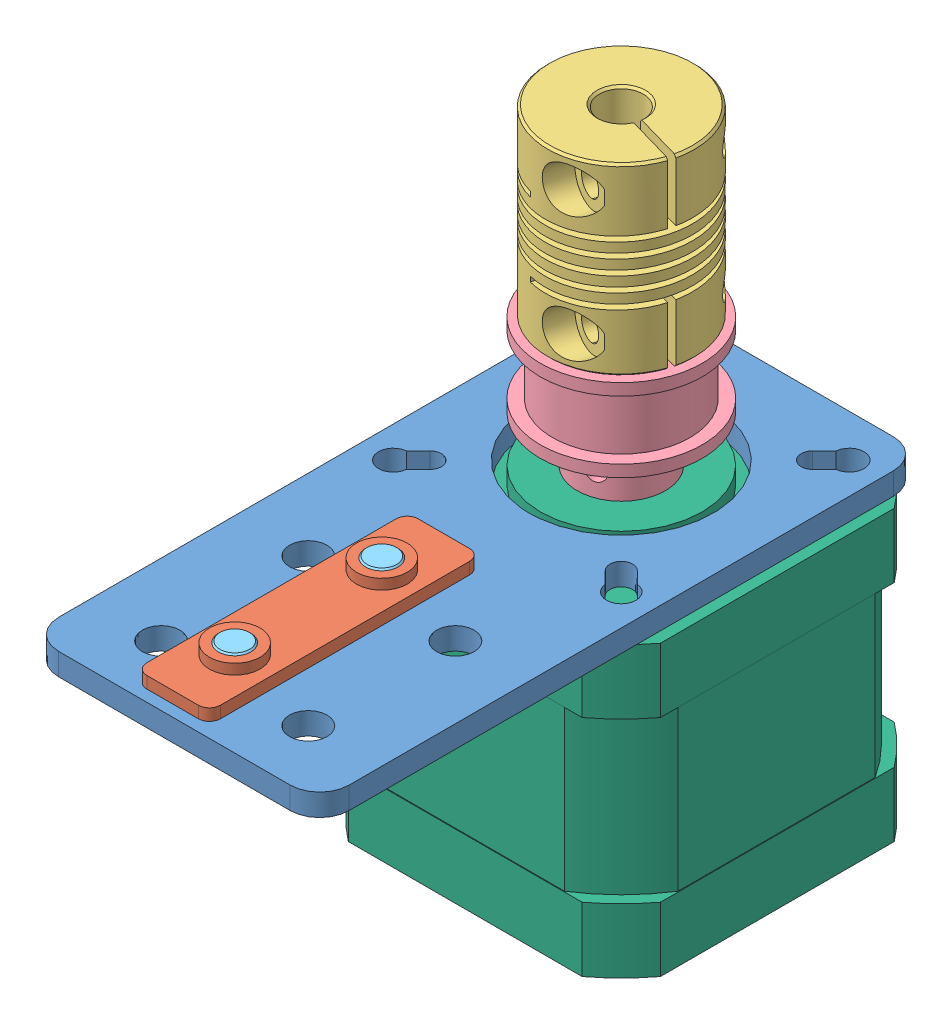
SolidWorks assembly MOTOR_MOUNT, configuration Default. Lengths in mm.
Overall size (42.42 84.14 82.24).
7 component instances, 6 part files, 14 mates.
Components (placement in the parent):
- MOD_NEMA_17_MOUNT_PLATE-1: MOD_NEMA_17_MOUNT_PLATE [Default] at (36.577 37.551 42.5841) size (39.5 3 82)
- Double Tee Nut-1: Double Tee Nut [Default] at (41.577 42.351 103.5741) x (0 0 -1) z (0 1 0) size (36.88 10 3)
- Flexible Coupling 5mm x 6mm-1: Flexible Coupling 5mm x 6mm [Default] at (36.577 57.451 42.5841) x (0.961283 0 0.275565) z (0 -1 0) size (21.03 20 25)
- GT2 Timing Pulley 30 Tooth-1: GT2 Timing Pulley 30 Tooth [Default] at (36.577 39.951 42.5841) x (0 1 0) z (0.35449 0 0.93506) size (17.5 22 22)
- LP_SH_SCREW_M5_8mm-1: LP_SH_SCREW_M5_8mm [M5 x 8] at (36.577 45.551 95.1341) x (0 1 0) z (0 0 1) size (9.62 9 9)
- LP_SH_SCREW_M5_8mm-2: LP_SH_SCREW_M5_8mm [M5 x 8] at (36.577 45.551 75.1341) x (0 1 0) z (0 0 1) size (9.62 9 9)
- NEMA_17_MOTOR-1: NEMA_17_MOTOR [Default] at (36.577 37.551 42.5841) x (1 0 0) z (0 1 0) size (42.42 42.42 60.45)
Mates (geometry in assembly coordinates):
- Concentric1: concentric anti-aligned: cylinder of MOD_NEMA_17_MOUNT_PLATE-1 through (36.577 40.551 75.1341) axis (0 -1 0) radius 2.55; cylinder of Double Tee Nut-1 through (36.577 45.351 75.1341) axis (0 1 0) radius 2.1
- Concentric2: concentric anti-aligned: cylinder of MOD_NEMA_17_MOUNT_PLATE-1 through (36.577 40.551 95.1341) axis (0 -1 0) radius 2.55; cylinder of Double Tee Nut-1 through (36.577 45.351 95.1341) axis (0 1 0) radius 2.1
- Distance2: distance = 1.8 mm anti-aligned: plane of Double Tee Nut-1 through (33.077 42.351 68.1941) normal (0 -1 0); plane of MOD_NEMA_17_MOUNT_PLATE-1 through (20.827 40.551 99.3341) normal (0 1 0)
- Coincident10: coincident anti-aligned: plane of Flexible Coupling 5mm x 6mm-1 through (36.577 57.451 42.5841) normal (0 -1 0); plane of GT2 Timing Pulley 30 Tooth-1 through (26.2913 57.451 46.4835) normal (0 1 0)
- Concentric101: concentric anti-aligned: cylinder of MOD_NEMA_17_MOUNT_PLATE-1 through (36.577 40.551 95.1341) axis (0 -1 0) radius 2.55; cylinder of LP_SH_SCREW_M5_8mm-1 through (36.577 37.551 95.1341) axis (0 1 0) radius 2.5
- Coincident111: coincident anti-aligned: plane of MOD_NEMA_17_MOUNT_PLATE-1 through (20.827 37.551 99.3341) normal (0 -1 0); plane of LP_SH_SCREW_M5_8mm-1 through (32.4156 37.551 95.1341) normal (0 1 0)
- Concentric111: concentric anti-aligned: cylinder of MOD_NEMA_17_MOUNT_PLATE-1 through (36.577 40.551 75.1341) axis (0 -1 0) radius 2.55; cylinder of LP_SH_SCREW_M5_8mm-2 through (36.577 37.551 75.1341) axis (0 1 0) radius 2.5
- Coincident121: coincident anti-aligned: plane of MOD_NEMA_17_MOUNT_PLATE-1 through (20.827 37.551 99.3341) normal (0 -1 0); plane of LP_SH_SCREW_M5_8mm-2 through (32.4156 37.551 75.1341) normal (0 1 0)
- Concentric112: concentric aligned: cylinder of MOD_NEMA_17_MOUNT_PLATE-1 through (36.577 40.551 42.5841) axis (0 -1 0) radius 12.5; cylinder of NEMA_17_MOTOR-1 through (36.577 39.951 42.5841) axis (0 -1 0) radius 11
- Coincident122: coincident anti-aligned: plane of MOD_NEMA_17_MOUNT_PLATE-1 through (20.827 37.551 99.3341) normal (0 -1 0); plane of NEMA_17_MOTOR-1 through (36.577 37.551 42.5841) normal (0 1 0)
- Parallel1: parallel aligned: plane of MOD_NEMA_17_MOUNT_PLATE-1 through (56.327 40.551 99.3341) normal (1 0 0); plane of NEMA_17_MOTOR-1 through (57.786 -1.689 63.7931) normal (1 0 0)
- Concentric113: concentric anti-aligned: cylinder of GT2 Timing Pulley 30 Tooth-1 through (36.577 39.951 42.5841) axis (0 1 0) radius 2.5; cylinder of NEMA_17_MOTOR-1 through (36.577 58.761 42.5841) axis (0 -1 0) radius 2.5
- Coincident127: coincident anti-aligned: plane of GT2 Timing Pulley 30 Tooth-1 through (34.2394 39.951 43.4703) normal (0 -1 0); plane of NEMA_17_MOTOR-1 through (36.577 39.951 42.5841) normal (0 1 0)
- Concentric114: concentric aligned: cylinder of Flexible Coupling 5mm x 6mm-1 through (36.577 82.451 42.5841) axis (0 -1 0) radius 2.5; cylinder of NEMA_17_MOTOR-1 through (36.577 58.761 42.5841) axis (0 -1 0) radius 2.5
